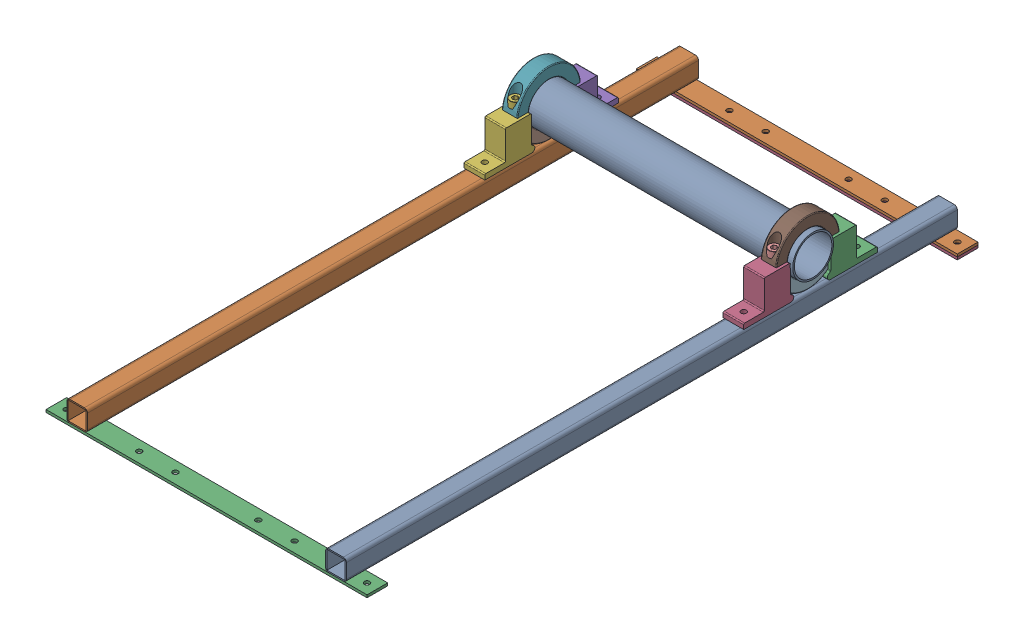
SolidWorks assembly ArmAttachment^Robot, configuration Default. Lengths in mm.
Overall size (393.7 109.75 749.3).
12 component instances, 5 part files, 34 mates.
Components (placement in the parent):
- Axel-1: Axel [Default] at (-224.099 114.3735 -473.1096) x (0 0.944355 0.328929) z (-1 0 0) size (50 50 349.25)
- CrossBarsMetalStrap-1: CrossBarsMetalStrap [Default] at (-398.7995 48.386 -640.4555) size (393.7 3.17 25.4)
- CrossBarsMetalStrap-2: CrossBarsMetalStrap [Default] at (-398.7995 48.386 83.4445) size (393.7 3.17 25.4)
- CrossBarsMetalStrap-3: CrossBarsMetalStrap [Default] at (-398.7995 45.211 -640.4555) size (393.7 3.17 25.4)
- 6063K26_Clamping Two-Piece Shaft Collar-1: 6063K26_Clamping Two-Piece Shaft Collar [6063K26] at (-557.474 114.3735 -473.1096) x (0 0 -1) z (1 0 0) size (77.86 78 19.11)
- 6063K26_Clamping Two-Piece Shaft Collar-2: 6063K26_Clamping Two-Piece Shaft Collar [6063K26] at (-239.974 114.3735 -473.1096) x (0 0 -1) z (1 0 0) size (77.86 78 19.11)
- CrossFrameBar 1x1-1: CrossFrameBar 1x1 [Default] at (-239.974 62.6735 -278.5055) size (25.4 25.4 749.3)
- CrossFrameBar 1x1-2: CrossFrameBar 1x1 [Default] at (-557.474 62.6735 -278.5055) size (25.4 25.4 749.3)
- AxelCollarsToFrameAlignmentBlock-1: AxelCollarsToFrameAlignmentBlock [Default] at (-239.974 114.3735 -473.1096) x (0 0 -1) z (1 0 0) size (61.39 42.23 25.4)
- AxelCollarsToFrameAlignmentBlock-2: AxelCollarsToFrameAlignmentBlock [Default] at (-239.974 114.3735 -473.1096) x (0 0 1) z (-1 0 0) size (61.39 42.23 25.4)
- AxelCollarsToFrameAlignmentBlock-3: AxelCollarsToFrameAlignmentBlock [Default] at (-557.474 114.3735 -472.9494) x (0 0 -1) z (1 0 0) size (61.39 42.23 25.4)
- AxelCollarsToFrameAlignmentBlock-4: AxelCollarsToFrameAlignmentBlock [Default] at (-557.474 114.3735 -473.1096) x (0 0 1) z (-1 0 0) size (61.39 42.23 25.4)
Mates (geometry in assembly coordinates):
- Width3: width anti-aligned: plane of CrossFrameBar 1x1-1 through (-227.274 49.9735 96.1445) normal (1 0 0); plane of Axel-1 through (-570.174 49.9735 96.1445) normal (-1 0 0); plane of CrossFrameBar 1x1-2 through (-573.349 114.3735 -473.1096) normal (-1 0 0); plane of Axel-1 through (-224.099 114.3735 -473.1096) normal (1 0 0)
- Coincident97: coincident anti-aligned: plane of CrossFrameBar 1x1-1 through (-252.674 49.9735 96.1445) normal (0 -1 0); plane of CrossBarsMetalStrap-1 through (-398.7995 49.9735 -640.4555) normal (0 1 0)
- Coincident100: coincident aligned: plane of CrossBarsMetalStrap-1 through (-201.9495 49.9735 -627.7555) normal (1 0 0); plane of CrossBarsMetalStrap-2 through (-201.9495 49.9735 96.1445) normal (1 0 0)
- Tangent2: tangent anti-aligned: plane of CrossFrameBar 1x1-2 through (-570.174 75.3735 96.1445) normal (0 1 0); cylinder of 6063K26_Clamping Two-Piece Shaft Collar-1 through (-547.974 114.3735 -473.1096) axis (-1 0 0) radius 39
- Width6: width anti-aligned: plane of 6063K26_Clamping Two-Piece Shaft Collar-1 through (-566.974 114.3735 -473.1096) normal (-1 0 0); plane of CrossFrameBar 1x1-2 through (-547.974 114.3735 -473.1096) normal (1 0 0); plane of 6063K26_Clamping Two-Piece Shaft Collar-1 through (-544.774 49.9735 96.1445) normal (1 0 0); plane of CrossFrameBar 1x1-2 through (-570.174 49.9735 96.1445) normal (-1 0 0)
- Parallel2: parallel aligned: plane of CrossFrameBar 1x1-2 through (-570.174 75.3735 96.1445) normal (0 1 0); plane of 6063K26_Clamping Two-Piece Shaft Collar-1 through (-547.974 111.2535 -497.9142) normal (0 1 0)
- Concentric14: concentric aligned: cylinder of 6063K26_Clamping Two-Piece Shaft Collar-1 through (-547.974 114.3735 -473.1096) axis (-1 0 0) radius 25; cylinder of 6063K26_Clamping Two-Piece Shaft Collar-2 through (-230.474 114.3735 -473.1096) axis (-1 0 0) radius 25
- Tangent1: tangent anti-aligned: plane of CrossFrameBar 1x1-1 through (-252.674 75.3735 96.1445) normal (0 1 0); cylinder of 6063K26_Clamping Two-Piece Shaft Collar-2 through (-230.474 114.3735 -473.1096) axis (-1 0 0) radius 39
- Parallel1: parallel aligned: plane of CrossFrameBar 1x1-1 through (-252.674 75.3735 96.1445) normal (0 1 0); plane of 6063K26_Clamping Two-Piece Shaft Collar-2 through (-230.474 111.2535 -497.9142) normal (0 1 0)
- Width5: width anti-aligned: plane of 6063K26_Clamping Two-Piece Shaft Collar-2 through (-249.474 114.3735 -473.1096) normal (-1 0 0); plane of CrossFrameBar 1x1-1 through (-230.474 114.3735 -473.1096) normal (1 0 0); plane of 6063K26_Clamping Two-Piece Shaft Collar-2 through (-227.274 49.9735 96.1445) normal (1 0 0); plane of CrossFrameBar 1x1-1 through (-252.674 49.9735 96.1445) normal (-1 0 0)
- Coincident108: coincident aligned: line of 6063K26_Clamping Two-Piece Shaft Collar-2 through (-231.424 111.2535 -511.9846) axis (-1 0 0); line of AxelCollarsToFrameAlignmentBlock-1 through (-230.3855 111.2535 -511.9846) axis (-1 0 0)
- Coincident111: coincident anti-aligned: line of 6063K26_Clamping Two-Piece Shaft Collar-2 through (-231.424 111.2535 -434.2346) axis (-1 0 0); line of AxelCollarsToFrameAlignmentBlock-2 through (-249.5625 111.2535 -434.2346) axis (1 0 0)
- Coincident91: coincident aligned: plane of CrossFrameBar 1x1-1 through (-239.974 62.6735 -653.1555) normal (0 0 -1); plane of CrossFrameBar 1x1-2 through (-557.474 62.6735 -653.1555) normal (0 0 -1)
- Distance20: distance = 292.1 mm anti-aligned: plane of CrossFrameBar 1x1-2 through (-544.774 49.9735 96.1445) normal (1 0 0); plane of CrossFrameBar 1x1-1 through (-252.674 49.9735 96.1445) normal (-1 0 0)
- Coincident94: coincident aligned: plane of CrossFrameBar 1x1-1 through (-252.674 75.3735 96.1445) normal (0 1 0); plane of CrossFrameBar 1x1-2 through (-570.174 75.3735 96.1445) normal (0 1 0)
- Coincident106: coincident anti-aligned: plane of CrossFrameBar 1x1-1 through (-252.674 75.3735 96.1445) normal (0 1 0); plane of AxelCollarsToFrameAlignmentBlock-1 through (-227.274 75.3735 -497.4891) normal (0 -1 0)
- Coincident107: coincident aligned: plane of CrossFrameBar 1x1-1 through (-227.274 49.9735 96.1445) normal (1 0 0); plane of AxelCollarsToFrameAlignmentBlock-1 through (-227.274 114.3735 -473.1096) normal (1 0 0)
- Coincident109: coincident aligned: plane of CrossFrameBar 1x1-1 through (-227.274 49.9735 96.1445) normal (1 0 0); plane of AxelCollarsToFrameAlignmentBlock-2 through (-227.274 114.3735 -473.1096) normal (1 0 0)
- Coincident110: coincident anti-aligned: plane of CrossFrameBar 1x1-1 through (-252.674 75.3735 96.1445) normal (0 1 0); plane of AxelCollarsToFrameAlignmentBlock-2 through (-252.674 75.3735 -448.7301) normal (0 -1 0)
- Concentric15: concentric anti-aligned: cylinder of Axel-1 through (-573.349 114.3735 -473.1096) axis (1 0 0) radius 25; cylinder of 6063K26_Clamping Two-Piece Shaft Collar-2 through (-230.474 114.3735 -473.1096) axis (-1 0 0) radius 25
- Distance21: distance = 98.0914 mm aligned: plane of AxelCollarsToFrameAlignmentBlock-1 through (-227.274 75.3735 -555.0642) normal (0 0 -1); plane of CrossFrameBar 1x1-1 through (-239.974 62.6735 -653.1555) normal (0 0 -1)
- Coincident115: coincident aligned: plane of CrossBarsMetalStrap-1 through (-595.6495 49.9735 -653.1555) normal (0 0 -1); plane of CrossFrameBar 1x1-1 through (-239.974 62.6735 -653.1555) normal (0 0 -1)
- Coincident116: coincident anti-aligned: plane of CrossBarsMetalStrap-1 through (-398.7995 46.7985 -640.4555) normal (0 -1 0); plane of CrossBarsMetalStrap-3 through (-398.7995 46.7985 -640.4555) normal (0 1 0)
- Coincident117: coincident anti-aligned: plane of CrossBarsMetalStrap-2 through (-398.7995 49.9735 83.4445) normal (0 1 0); plane of CrossFrameBar 1x1-1 through (-252.674 49.9735 96.1445) normal (0 -1 0)
- Coincident118: coincident aligned: plane of CrossBarsMetalStrap-2 through (-595.6495 49.9735 96.1445) normal (0 0 1); plane of CrossFrameBar 1x1-1 through (-239.974 62.6735 96.1445) normal (0 0 1)
- Distance22: distance = 25.3245 mm aligned: plane of CrossBarsMetalStrap-2 through (-201.9495 49.9735 96.1445) normal (1 0 0); plane of CrossFrameBar 1x1-1 through (-227.274 49.9735 96.1445) normal (1 0 0)
- Coincident120: coincident aligned: plane of CrossBarsMetalStrap-1 through (-595.6495 49.9735 -627.7555) normal (-1 0 0); plane of CrossBarsMetalStrap-3 through (-595.6495 46.7985 -627.7555) normal (-1 0 0)
- Parallel3: parallel aligned: plane of CrossBarsMetalStrap-1 through (-398.7995 46.7985 -640.4555) normal (0 -1 0); plane of CrossBarsMetalStrap-3 through (-398.7995 43.6235 -640.4555) normal (0 -1 0)
- Coincident122: coincident aligned: plane of CrossBarsMetalStrap-1 through (-595.6495 49.9735 -627.7555) normal (0 0 1); plane of CrossBarsMetalStrap-3 through (-595.6495 46.7985 -627.7555) normal (0 0 1)
- Coincident123: coincident anti-aligned: plane of CrossFrameBar 1x1-2 through (-570.174 75.3735 96.1445) normal (0 1 0); plane of AxelCollarsToFrameAlignmentBlock-3 through (-544.774 75.3735 -497.3289) normal (0 -1 0)
- Coincident125: coincident aligned: plane of CrossFrameBar 1x1-2 through (-570.174 49.9735 96.1445) normal (-1 0 0); plane of AxelCollarsToFrameAlignmentBlock-3 through (-570.174 114.3735 -472.9494) normal (-1 0 0)
- Concentric16: concentric anti-aligned: cylinder of 6063K26_Clamping Two-Piece Shaft Collar-1 through (-557.474 98.4935 -504.9494) axis (0 -1 0) radius 4; cylinder of AxelCollarsToFrameAlignmentBlock-3 through (-557.474 85.8535 -504.9494) axis (0 1 0) radius 4
- Concentric17: concentric anti-aligned: cylinder of 6063K26_Clamping Two-Piece Shaft Collar-1 through (-557.474 98.4935 -441.1096) axis (0 -1 0) radius 4; cylinder of AxelCollarsToFrameAlignmentBlock-4 through (-557.474 85.8535 -441.1096) axis (0 1 0) radius 4
- Coincident126: coincident aligned: plane of CrossFrameBar 1x1-2 through (-570.174 49.9735 96.1445) normal (-1 0 0); plane of AxelCollarsToFrameAlignmentBlock-4 through (-570.174 114.3735 -473.1096) normal (-1 0 0)
